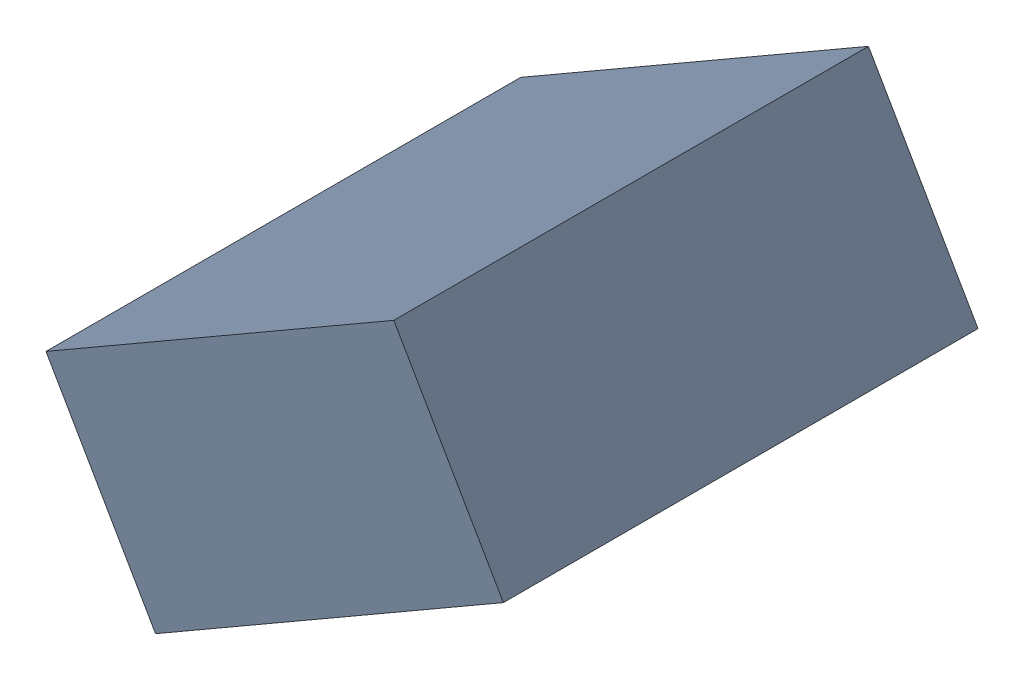
SolidWorks assembly C21_TDA5, configuration Standard. Lengths in mm.
Overall size (1.25 1.07 1.3).
2 component instances, 1 part files, 0 mates.
Components (placement in the parent):
- 885542920-1: 885542920 [Standard] at (-39.4823 -31.3904 0) size (1.25 1.07 1.3)
  - Extruded_24-1: Extruded_24 [Standard] at origin size (1.25 1.07 1.3)
